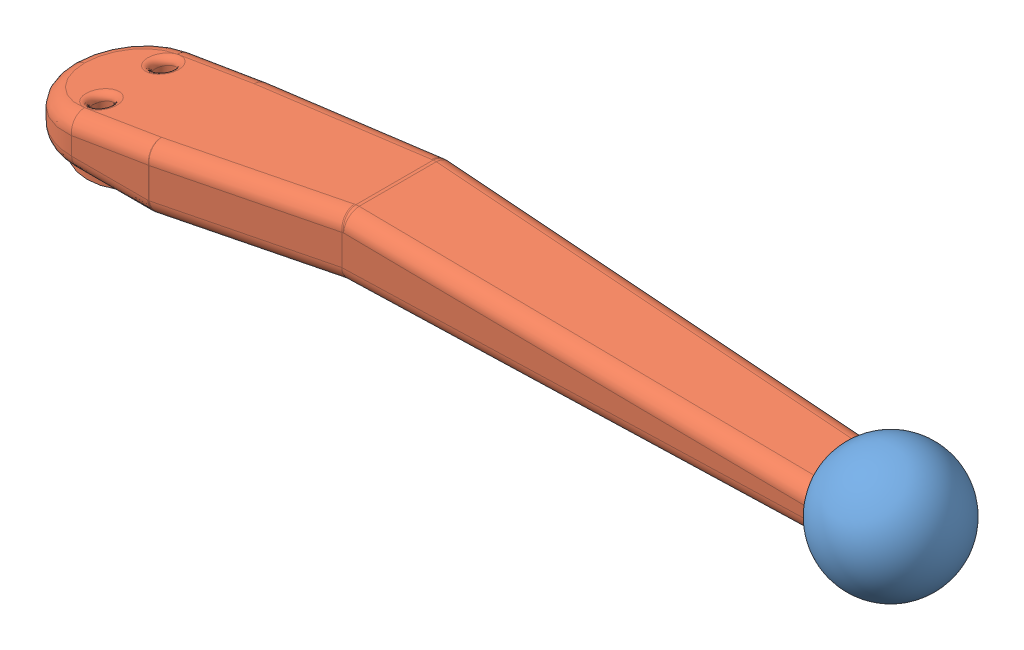
SolidWorks assembly LOWER_LEG_ASSEMBLY, configuration Default. Lengths in mm.
Overall size (264.38 40.5 40.01).
2 component instances, 2 part files, 1 mates.
Components (placement in the parent):
- foot-1: foot [Default] at (163.4965 57.2841 -0.5063) x (0 1 0) z (0 0 -1) size (40 38.91 40)
- LOWER_LEG_MODULE-1: LOWER_LEG_MODULE [Default] at (3.4965 60.7841 -0.4954) size (224.38 33.97 40)
Mates (geometry in assembly coordinates):
- Coincident2: coincident anti-aligned: plane of foot-1 through (136.4965 50.7841 -13.0063) normal (0 1 0); plane of LOWER_LEG_MODULE-1 through (3.4965 50.7841 -0.4954) normal (0 -1 0)
